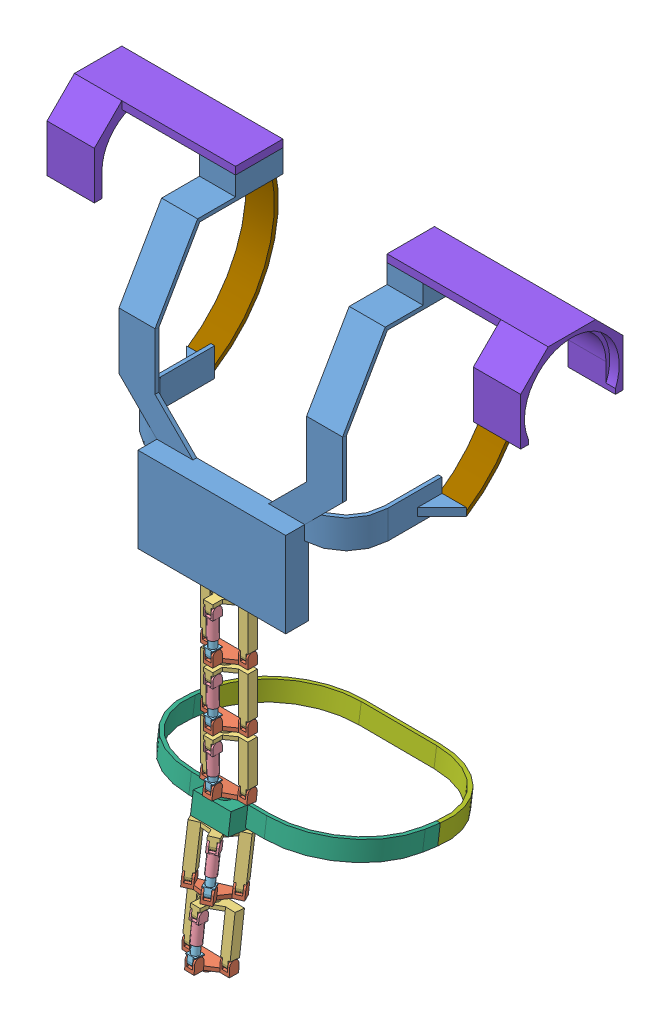
SolidWorks assembly torso, configuration Default. Lengths in mm.
Overall size (500 639.5 227.87).
27 component instances, 9 part files, 65 mates.
Components (placement in the parent):
- torso_back-1: torso_back [Default] at (168.5824 184.5536 298.8783) size (296 295.94 155)
- unit_p1_v0.2-2: unit_p1_v0.2 [Default] at (168.6013 82.5536 304.7784) x (-0.999986 0 -0.005247) z (-0.005247 0 0.999986) size (50 18 27)
- unit_p2_v0.2-1: unit_p2_v0.2 [Default] at (168.6013 132.5536 304.7784) x (0.999986 0 0.005247) z (-0.005247 0 0.999986) size (50 58 27)
- unit_pole_a-1: unit_pole_a [Default] at (168.5121 132.5536 321.7781) x (0.005247 0 -0.999986) z (-0.999986 0 -0.005247) size (10 31 10)
- unit_pole_b-1: unit_pole_b [Default] at (168.5121 93.5536 321.7781) x (0.999986 0 0.005247) z (0.005247 0 -0.999986) size (10 29 10)
- unit_pole_b-2: unit_pole_b [Default] at (168.5121 31.5536 321.7781) x (0.999986 0 0.005247) z (0.005247 0 -0.999986) size (10 29 10)
- unit_pole_a-2: unit_pole_a [Default] at (168.5121 70.5536 321.7781) x (-0.005247 0 0.999986) z (0.999986 0 0.005247) size (10 31 10)
- unit_p1_v0.2-3: unit_p1_v0.2 [Default] at (168.6013 20.5536 304.7784) x (-0.999986 0 -0.005247) z (-0.005247 0 0.999986) size (50 18 27)
- unit_p2_v0.2-2: unit_p2_v0.2 [Default] at (168.6013 70.5536 304.7784) x (0.999986 0 0.005247) z (-0.005247 0 0.999986) size (50 58 27)
- unit_pole_b-3: unit_pole_b [Default] at (168.5128 -28.1292 321.6447) x (0.999986 0 0.005247) z (0.005247 0.004211 -0.999977) size (10 29 10)
- unit_pole_a-3: unit_pole_a [Default] at (168.512 8.5535 321.7992) x (-0.005247 -0.004211 0.999977) z (0.999986 0 0.005247) size (10 31 10)
- unit_p1_v0.2-4: unit_p1_v0.2 [Default] at (168.5977 -41.3997 305.4599) x (-0.999986 0 -0.005247) z (-0.005198 0.136309 0.990653) size (50 18 27)
- unit_p2_v0.2-3: unit_p2_v0.2 [Default] at (168.6013 8.5536 304.7784) x (0.999986 0 0.005247) z (-0.005247 0 0.999986) size (50 58 27)
- waist_back-1: waist_back [Default] at (168.5453 -69.2976 315.4558) x (-0.999986 0 -0.005247) z (0.005198 -0.136309 -0.990653) size (248 30 118)
- unit_p1_v0.2-5: unit_p1_v0.2 [Default] at (166.6634 -128.5389 317.6905) x (-0.875777 0.066418 0.478125) z (0.482134 0.071763 0.873153) size (50 18 27)
- unit_p2_v0.2-4: unit_p2_v0.2 [Default] at (166.814 -78.9829 311.0824) x (0.875777 -0.066418 -0.478125) z (0.482715 0.119032 0.867651) size (50 58 27)
- unit_pole_a-4: unit_pole_a [Default] at (175.0213 -76.959 325.8345) x (0.482715 0.118565 0.867715) z (0.875777 -0.066418 -0.478125) size (10 31 10)
- unit_pole_b-4: unit_pole_b [Default] at (174.9838 -116.3986 331.2444) x (0.875777 -0.066418 -0.478125) z (-0.482715 -0.118565 -0.867715) size (10 29 10)
- unit_pole_a-5: unit_pole_a [Default] at (168.1301 -138.9511 335.3185) x (0.001094 0.093542 0.995615) z (0.999719 -0.023681 0.001126) size (10 31 10)
- unit_pole_b-5: unit_pole_b [Default] at (167.174 -179.1321 339.0947) x (0.999719 -0.023681 0.001126) z (-0.001094 -0.093542 -0.995615) size (10 29 10)
- unit_p1_v0.2-6: unit_p1_v0.2 [Default] at (166.9268 -190.347 322.7297) x (-0.999719 0.023681 -0.001126) z (-0.000785 0.014404 0.999896) size (50 18 27)
- unit_p2_v0.2-5: unit_p2_v0.2 [Default] at (168.1109 -140.5646 318.3886) x (0.999719 -0.023681 0.001126) z (0.001126 0.094871 0.995489) size (50 58 27)
- front_a-1: front_a [Default] at (169.1073 -83.0283 208.329) x (-0.999986 0 -0.005247) z (0.005198 -0.136309 -0.990653) size (248 20 84)
- torso_shoulder-1: torso_shoulder [默认] at (248.5824 436.4959 192.8783) x (0 0 -1) z (1 0 0) size (108 79.05 170)
- torso_shoulder-2: torso_shoulder [默认] at (88.5824 436.4959 192.8783) x (0 0 1) z (-1 0 0) size (108 79.05 170)
- addtion_v0.1-1: addtion_v0.1 [Default] at (286.5824 379.2997 201.8783) size (30 213.78 67.22)
- addtion_v0.1-2: addtion_v0.1 [Default] at (20.5824 379.2997 201.8783) size (30 213.78 67.22)
Mates (geometry in assembly coordinates):
- 重合1: coincident anti-aligned: plane of torso_back-1 through (168.5824 136.5536 308.3783) normal (0 -1 0); plane of unit_p2_v0.2-1 through (168.6013 136.5536 304.7784) normal (0 1 0)
- 同心1: concentric anti-aligned: cylinder of torso_back-1 through (168.5824 136.5536 308.3783) axis (0 1 0) radius 6; cylinder of unit_p2_v0.2-1 through (168.5824 140.5536 308.3783) axis (0 -1 0) radius 7
- 重合2: coincident anti-aligned: plane of unit_p1_v0.2-2 through (145.4862 82.5536 326.6574) normal (0.999986 0 0.005247); plane of unit_p2_v0.2-1 through (145.4862 82.5536 326.6574) normal (-0.999986 0 -0.005247)
- 同心2: concentric anti-aligned: cylinder of unit_p1_v0.2-2 through (193.6009 87.5536 304.9095) axis (-0.999986 0 -0.005247) radius 5; cylinder of unit_p2_v0.2-1 through (143.6016 87.5536 304.6472) axis (0.999986 0 0.005247) radius 5
- 同心4: concentric anti-aligned: cylinder of unit_p2_v0.2-1 through (143.5124 127.5536 321.647) axis (0.999986 0 0.005247) radius 5; cylinder of unit_pole_a-1 through (223.5113 127.5536 322.0667) axis (-0.999986 0 -0.005247) radius 5
- 重合3: coincident anti-aligned: plane of unit_p2_v0.2-1 through (165.4859 122.5536 326.7623) normal (-0.999986 0 -0.005247); plane of unit_pole_a-1 through (165.2235 132.5536 376.7616) normal (0.999986 0 0.005247)
- 同心5: concentric anti-aligned: cylinder of unit_p1_v0.2-2 through (193.5117 87.5536 321.9093) axis (-0.999986 0 -0.005247) radius 5; cylinder of unit_pole_b-1 through (125.5127 87.5536 321.5525) axis (0.999986 0 0.005247) radius 5
- 重合4: coincident anti-aligned: plane of unit_p1_v0.2-2 through (165.4859 82.5536 326.7623) normal (0.999986 0 0.005247); plane of unit_pole_b-1 through (165.297 82.5536 362.7618) normal (-0.999986 0 -0.005247)
- 同心6: concentric anti-aligned: cylinder of unit_pole_a-1 through (168.5121 101.5536 321.7781) axis (0 1 0) radius 5; cylinder of unit_pole_b-1 through (168.5121 111.5536 321.7781) axis (0 -1 0) radius 4
- 同心7: concentric anti-aligned: cylinder of unit_p1_v0.2-2 through (168.5824 74.5536 308.3783) axis (0 1 0) radius 6; cylinder of unit_p2_v0.2-2 through (168.5824 78.5536 308.3783) axis (0 -1 0) radius 7
- 重合5: coincident anti-aligned: plane of unit_p1_v0.2-2 through (168.5824 74.5536 308.3783) normal (0 -1 0); plane of unit_p2_v0.2-2 through (168.6013 74.5536 304.7784) normal (0 1 0)
- 同心8: concentric aligned: cylinder of unit_pole_a-2 through (113.5128 65.5536 321.4896) axis (0.999986 0 0.005247) radius 5; cylinder of unit_p2_v0.2-2 through (143.5124 65.5536 321.647) axis (0.999986 0 0.005247) radius 5
- 重合6: coincident anti-aligned: plane of unit_pole_a-2 through (171.8006 70.5536 266.7946) normal (-0.999986 0 -0.005247); plane of unit_p2_v0.2-2 through (171.4858 60.5536 326.7938) normal (0.999986 0 0.005247)
- 同心9: concentric anti-aligned: cylinder of unit_p1_v0.2-3 through (193.6009 25.5536 304.9095) axis (-0.999986 0 -0.005247) radius 5; cylinder of unit_p2_v0.2-2 through (143.6016 25.5536 304.6472) axis (0.999986 0 0.005247) radius 5
- 重合7: coincident anti-aligned: plane of unit_p1_v0.2-3 through (191.4855 20.5536 326.8987) normal (-0.999986 0 -0.005247); plane of unit_p2_v0.2-2 through (191.4855 20.5536 326.8987) normal (0.999986 0 0.005247)
- 同心10: concentric anti-aligned: cylinder of unit_pole_b-2 through (125.5127 25.5536 321.5525) axis (0.999986 0 0.005247) radius 5; cylinder of unit_p1_v0.2-3 through (193.5117 25.5536 321.9093) axis (-0.999986 0 -0.005247) radius 5
- 重合8: coincident anti-aligned: plane of unit_pole_b-2 through (165.297 20.5536 362.7618) normal (-0.999986 0 -0.005247); plane of unit_p1_v0.2-3 through (165.4859 20.5536 326.7623) normal (0.999986 0 0.005247)
- 同心11: concentric anti-aligned: cylinder of unit_pole_b-2 through (168.5121 49.5536 321.7781) axis (0 -1 0) radius 4; cylinder of unit_pole_a-2 through (168.5121 39.5536 321.7781) axis (0 1 0) radius 5
- 重合9: coincident anti-aligned: plane of unit_p1_v0.2-3 through (168.5824 12.5536 308.3783) normal (0 -1 0); plane of unit_p2_v0.2-3 through (168.6013 12.5536 304.7784) normal (0 1 0)
- 同心12: concentric anti-aligned: cylinder of unit_p1_v0.2-3 through (168.5824 12.5536 308.3783) axis (0 1 0) radius 6; cylinder of unit_p2_v0.2-3 through (168.5824 16.5536 308.3783) axis (0 -1 0) radius 7
- 同心13: concentric anti-aligned: cylinder of unit_p1_v0.2-4 through (193.6009 -36.4464 304.9095) axis (-0.999986 0 -0.005247) radius 5; cylinder of unit_p2_v0.2-3 through (143.6016 -36.4464 304.6472) axis (0.999986 0 0.005247) radius 5
- 重合10: coincident anti-aligned: plane of unit_p1_v0.2-4 through (185.4831 -38.401 327.3435) normal (0.999986 0 0.005247); plane of unit_p2_v0.2-3 through (185.4856 -41.4464 326.8673) normal (-0.999986 0 -0.005247)
- 同心14: concentric anti-aligned: cylinder of unit_pole_b-3 through (125.5135 -34.1292 321.3939) axis (0.999986 0 0.005247) radius 5; cylinder of unit_p1_v0.2-4 through (193.5126 -34.1292 321.7506) axis (-0.999986 0 -0.005247) radius 5
- 重合11: coincident anti-aligned: plane of unit_pole_b-3 through (165.2979 -39.3018 362.5817) normal (-0.999986 0 -0.005247); plane of unit_p1_v0.2-4 through (165.4834 -38.401 327.2385) normal (0.999986 0 0.005247)
- 同心15: concentric aligned: cylinder of unit_pole_a-3 through (113.5128 3.5536 321.4896) axis (0.999986 0 0.005247) radius 5; cylinder of unit_p2_v0.2-3 through (143.5124 3.5536 321.647) axis (0.999986 0 0.005247) radius 5
- 重合12: coincident anti-aligned: plane of unit_pole_a-3 through (171.8005 8.7851 266.8162) normal (-0.999986 0 -0.005247); plane of unit_p2_v0.2-3 through (171.4858 -1.4464 326.7938) normal (0.999986 0 0.005247)
- 同心16: concentric anti-aligned: cylinder of unit_pole_b-3 through (168.5124 -10.1294 321.7205) axis (0.000022 -0.999991 -0.004211) radius 4; cylinder of unit_pole_a-3 through (168.5127 -22.4462 321.6687) axis (-0.000022 0.999991 0.004211) radius 5
- 重合13: coincident anti-aligned: plane of unit_p1_v0.2-4 through (168.5733 -48.8344 310.1167) normal (-0.000715 -0.990666 0.136307); plane of waist_back-1 through (209.0379 -61.034 221.6632) normal (0.000715 0.990666 -0.136307)
- 同心17: concentric anti-aligned: cylinder of unit_p1_v0.2-4 through (168.5733 -48.8344 310.1167) axis (0.000715 0.990666 -0.136307) radius 6; cylinder of waist_back-1 through (168.5761 -44.8717 309.5715) axis (-0.000715 -0.990666 0.136307) radius 7
- 平行1: parallel aligned: plane of unit_p1_v0.2-4 through (143.6212 -46.044 300.9207) normal (0.005198 -0.136309 -0.990653); plane of waist_back-1 through (148.6086 -69.9426 303.3267) normal (0.005198 -0.136309 -0.990653)
- 平行2: parallel aligned: plane of unit_p2_v0.2-2 through (193.6272 74.5536 299.9096) normal (0.005247 0 -0.999986); plane of unit_p2_v0.2-3 through (193.6272 12.5536 299.9096) normal (0.005247 0 -0.999986)
- 平行3: parallel aligned: plane of unit_p2_v0.2-1 through (193.6272 136.5536 299.9096) normal (0.005247 0 -0.999986); plane of unit_p2_v0.2-2 through (193.6272 74.5536 299.9096) normal (0.005247 0 -0.999986)
- 同心18: concentric anti-aligned: cylinder of waist_back-1 through (168.5547 -74.5917 313.6607) axis (0.000715 0.990666 -0.136307) radius 6; cylinder of unit_p2_v0.2-4 through (168.5575 -70.629 313.1155) axis (-0.000715 -0.990666 0.136307) radius 7
- 重合15: coincident anti-aligned: plane of waist_back-1 through (168.5547 -74.5917 313.6607) normal (-0.000715 -0.990666 0.136307); plane of unit_p2_v0.2-4 through (166.8169 -75.0202 310.5371) normal (0.000715 0.990666 -0.136307)
- 同心19: concentric anti-aligned: cylinder of unit_p1_v0.2-5 through (188.6763 -125.2233 305.2631) axis (-0.875777 0.066418 0.478125) radius 5; cylinder of unit_p2_v0.2-4 through (144.8874 -121.9024 329.1693) axis (0.875777 -0.066418 -0.478125) radius 5
- 重合16: coincident anti-aligned: plane of unit_p1_v0.2-5 through (157.1275 -125.4325 347.8968) normal (0.875777 -0.066418 -0.478125); plane of unit_p2_v0.2-4 through (157.2551 -124.3699 347.9829) normal (-0.875777 0.066418 0.478125)
- 同心20: concentric anti-aligned: cylinder of unit_p1_v0.2-5 through (196.8726 -124.0033 320.1067) axis (-0.875777 0.066418 0.478125) radius 5; cylinder of unit_pole_b-4 through (137.3197 -119.4869 352.6191) axis (0.875777 -0.066418 -0.478125) radius 5
- 重合17: coincident anti-aligned: plane of unit_p1_v0.2-5 through (174.6431 -126.7609 338.3343) normal (0.875777 -0.066418 -0.478125); plane of unit_pole_b-4 through (192.1374 -122.2361 369.7499) normal (-0.875777 0.066418 0.478125)
- 同心21: concentric aligned: cylinder of unit_p2_v0.2-4 through (153.1222 -80.2522 338.4671) axis (0.875777 -0.066418 -0.478125) radius 5; cylinder of unit_pole_a-4 through (126.8489 -78.2597 352.8108) axis (0.875777 -0.066418 -0.478125) radius 5
- 重合18: coincident anti-aligned: plane of unit_p2_v0.2-4 through (180.0539 -86.4701 330.0994) normal (0.875777 -0.066418 -0.478125); plane of unit_pole_a-4 through (151.0994 -83.6794 276.6758) normal (-0.875777 0.066418 0.478125)
- 同心22: concentric anti-aligned: cylinder of unit_pole_a-4 through (174.9921 -107.6714 330.0473) axis (0.000943 0.990722 -0.135897) radius 5; cylinder of unit_pole_b-4 through (175.0008 -98.5655 328.7982) axis (-0.000943 -0.990722 0.135897) radius 4
- 重合19: coincident anti-aligned: plane of unit_p1_v0.2-5 through (168.2097 -136.2422 321.5928) normal (-0.023681 -0.995208 0.094871); plane of unit_p2_v0.2-5 through (168.2056 -136.5838 318.0091) normal (0.023681 0.995208 -0.094871)
- 同心23: concentric anti-aligned: cylinder of unit_p1_v0.2-5 through (168.2097 -136.2422 321.5928) axis (0.023681 0.995208 -0.094871) radius 6; cylinder of unit_p2_v0.2-5 through (168.3044 -132.2614 321.2134) axis (-0.023681 -0.995208 0.094871) radius 7
- 同心24: concentric anti-aligned: cylinder of unit_p1_v0.2-6 through (192.0382 -185.941 322.6859) axis (-0.999719 0.023681 -0.001126) radius 5; cylinder of unit_p2_v0.2-5 through (142.0523 -184.7569 322.6296) axis (0.999719 -0.023681 0.001126) radius 5
- 重合20: coincident anti-aligned: plane of unit_p1_v0.2-6 through (143.916 -189.4855 344.7015) normal (0.999719 -0.023681 0.001126); plane of unit_p2_v0.2-5 through (143.9581 -187.6932 345.007) normal (-0.999719 0.023681 -0.001126)
- 同心25: concentric anti-aligned: cylinder of unit_pole_b-5 through (124.044 -184.0858 339.6076) axis (0.999719 -0.023681 0.001126) radius 5; cylinder of unit_p1_v0.2-6 through (192.0249 -185.6961 339.6841) axis (-0.999719 0.023681 -0.001126) radius 5
- 重合21: coincident anti-aligned: plane of unit_pole_b-5 through (163.9592 -186.1745 380.9405) normal (-0.999719 0.023681 -0.001126); plane of unit_p1_v0.2-6 through (163.9103 -189.9591 344.724) normal (0.999719 -0.023681 0.001126)
- 同心26: concentric aligned: cylinder of unit_pole_a-5 through (113.0271 -142.6254 335.7243) axis (0.999719 -0.023681 0.001126) radius 5; cylinder of unit_p2_v0.2-5 through (143.0187 -143.3358 335.7581) axis (0.999719 -0.023681 0.001126) radius 5
- 重合22: coincident anti-aligned: plane of unit_pole_a-5 through (171.069 -144.167 280.5631) normal (-0.999719 0.023681 -0.001126); plane of unit_p2_v0.2-5 through (170.898 -148.5005 341.2414) normal (0.999719 -0.023681 0.001126)
- 同心27: concentric anti-aligned: cylinder of unit_pole_a-5 through (167.3959 -169.8065 338.2183) axis (0.023683 0.995334 -0.093542) radius 5; cylinder of unit_pole_b-5 through (167.6003 -161.2161 337.411) axis (-0.023683 -0.995334 0.093542) radius 4
- 重合23: coincident aligned: plane of waist_back-1 through (209.0379 -61.034 221.6632) normal (0.000715 0.990666 -0.136307); plane of front_a-1 through (129.1222 -63.2149 205.393) normal (0.000715 0.990666 -0.136307)
- 重合24: coincident anti-aligned: plane of waist_back-1 through (293.1199 -63.2149 206.2534) normal (0.005198 -0.136309 -0.990653); plane of front_a-1 through (293.1199 -63.2149 206.2534) normal (-0.005198 0.136309 0.990653)
- 重合25: coincident aligned: line of waist_back-1 through (293.1199 -63.2149 206.2534) axis (-0.000715 -0.990666 0.136307); line of front_a-1 through (293.1199 -63.2149 206.2534) axis (-0.000715 -0.990666 0.136307)
- 重合26: coincident aligned: plane of torso_back-1 through (248.5824 408.4959 257.8783) normal (-1 0 0); plane of torso_shoulder-1 through (248.5824 436.4959 192.8783) normal (-1 0 0)
- 重合27: coincident anti-aligned: plane of torso_back-1 through (168.5824 432.4959 298.8783) normal (0 1 0); plane of shoulder_p1-1 through (248.5824 432.4959 217.8783) normal (0 -1 0)
- 重合28: coincident aligned: plane of torso_back-1 through (168.5824 408.4959 167.8783) normal (0 0 -1); plane of shoulder_p1-1 through (248.5824 440.4959 167.8783) normal (0 0 -1)
- 重合29: coincident aligned: plane of torso_back-1 through (88.5824 408.4959 257.8783) normal (1 0 0); plane of torso_shoulder-2 through (88.5824 436.4959 192.8783) normal (1 0 0)
- 重合30: coincident aligned: plane of torso_back-1 through (50.5824 432.4959 217.8783) normal (0 0 1); plane of torso_shoulder-2 through (88.5824 440.4959 217.8783) normal (0 0 1)
- 重合31: coincident anti-aligned: plane of torso_back-1 through (168.5824 432.4959 298.8783) normal (0 1 0); plane of torso_shoulder-2 through (88.5824 432.4959 167.8783) normal (0 -1 0)
- 重合39: coincident anti-aligned: plane of torso_shoulder-1 through (248.5824 440.4959 167.8783) normal (0 0 -1); plane of addtion_v0.1-1 through (316.5824 440.4959 167.8783) normal (0 0 1)
- 重合40: coincident anti-aligned: line of torso_shoulder-1 through (248.5824 440.4959 167.8783) axis (1 0 0); line of addtion_v0.1-1 through (316.5824 440.4959 167.8783) axis (-1 0 0)
- 重合41: coincident anti-aligned: plane of torso_back-1 through (286.5824 408.4959 257.8783) normal (1 0 0); plane of addtion_v0.1-1 through (286.5824 348.5098 278.6052) normal (-1 0 0)
- 重合42: coincident anti-aligned: plane of torso_shoulder-2 through (88.5824 440.4959 167.8783) normal (0 0 -1); plane of addtion_v0.1-2 through (50.5824 440.4959 167.8783) normal (0 0 1)
- 重合43: coincident: plane of torso_shoulder-2 through (88.5824 440.4959 167.8783) normal (0 1 0); line of addtion_v0.1-2 through (50.5824 440.4959 167.8783) axis (-1 0 0)
- 重合44: coincident anti-aligned: plane of torso_back-1 through (50.5824 408.4959 257.8783) normal (-1 0 0); plane of addtion_v0.1-2 through (50.5824 348.5098 278.6052) normal (1 0 0)
